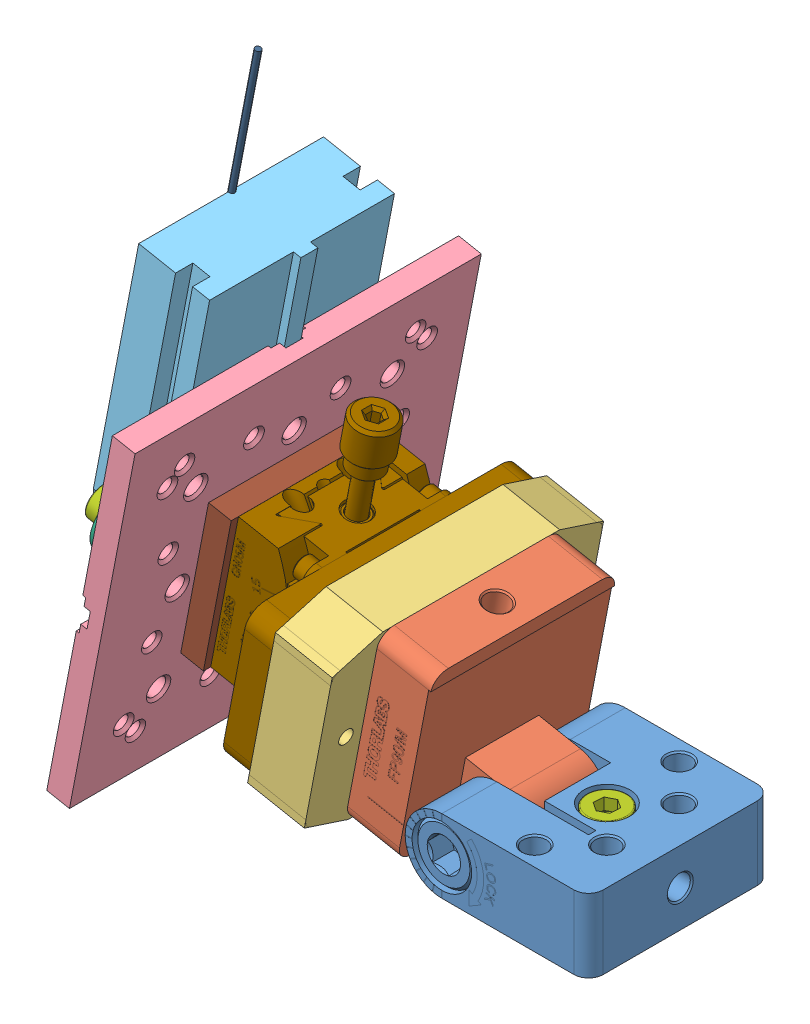
SolidWorks assembly FP90_M, configuration Default. Lengths in mm.
Overall size (94.61 108.26 59.94).
22 component instances, 12 part files, 54 mates.
Components (placement in the parent):
- FP90_M-Solidworks-1: FP90_M-Solidworks [Default] at (-4.5271 5.9477 40.2295) size (31.75 12.7 31.75)
- FP90_M-Solidworks_2-1: FP90_M-Solidworks_2 [Default] at (6.8553 4.8599 40.2422) x (0.189404 0.981899 0) z (0 0 1) size (31.75 22.1 31.75)
- Adaptador_GN05-M_FP90-M-1: Adaptador_GN05-M_FP90-M [Default] at (-11.9606 24.657 24.3481) x (0 0 -1) z (-0.981899 0.189404 0) size (47 31.7 10)
- MMP1_M-Solidworks-1: MMP1_M-Solidworks [Default] at (-31.0725 -5.8483 28.1014) x (-0.189404 -0.981899 0) z (0 0 -1) size (59.94 4.17 59.94)
- HFV002-Solidworks-1: HFV002-Solidworks [Default] at (-34.227 66.5773 14.0318) x (0 0 -1) z (0.189404 0.981899 0) size (32 13.8 82.5)
- AMA010-Solidworks-1: AMA010-Solidworks [Default] at (-49.437 40.346 4.0466) x (0.189404 0.981899 0) z (0 0 1) size (10.11 4.2 10.5)
- AMA010-Solidworks-2: AMA010-Solidworks [Default] at (-49.2897 40.3176 44.0516) x (0.189404 0.981899 0) z (0 0 1) size (10.11 4.2 10.5)
- socket head cap screw_iso_2-5: socket head cap screw_iso_2 [ISO 4762 M4 x 12 - 12N] at (-22.4725 20.3195 30.5981) x (0.981899 -0.189404 0) z (0.014939 0.077448 -0.996884) size (16 7 7)
- socket head cap screw_iso_2-6: socket head cap screw_iso_2 [ISO 4762 M3 x 8 - 8N] at (-26.521 27.4657 5.6481) x (0.981899 -0.189404 0) z (0.001715 0.008892 0.999959) size (11 5.5 5.5)
- socket head cap screw_iso_2-7: socket head cap screw_iso_2 [ISO 4762 M3 x 8 - 8N] at (-26.521 27.4657 43.0481) x (0.981899 -0.189404 0) z (0.001715 0.008892 0.999959) size (11 5.5 5.5)
- socket head cap screw_iso_2-8: socket head cap screw_iso_2 [ISO 4762 M4 x 16 - 16N] at (14.5229 18.3297 24.3545) x (0 -1 0) z (-0.546944 0 0.837169) size (20 7 7)
- plain washer small grade a_iso_2-1: plain washer small grade a_iso_2 [Washer ISO 7092 - 3] at (-49.838 39.621 4.2881) x (0.981899 -0.189404 0) z (0 0 1) size (0.5 6 6)
- plain washer small grade a_iso_2-2: plain washer small grade a_iso_2 [Washer ISO 7092 - 3] at (-49.6907 39.5926 44.2931) x (0.981899 -0.189404 0) z (0 0 1) size (0.5 6 6)
- socket head cap screw_iso_2-9: socket head cap screw_iso_2 [ISO 4762 M3 x 6 - 6N] at (-53.1274 40.2555 44.2931) x (0.981899 -0.189404 0) z (0.168238 0.872168 0.459369) size (9 5.5 5.5)
- socket head cap screw_iso_2-10: socket head cap screw_iso_2 [ISO 4762 M3 x 6 - 6N] at (-53.2747 40.284 4.2881) x (0.981899 -0.189404 0) z (-0.019637 -0.101802 0.994611) size (9 5.5 5.5)
- GN05_M-Solidworks-1: GN05_M-Solidworks [Default] at (-23.9281 14.0721 47.8381) x (0 0 -1) z (0.189404 0.981899 0) size (46.99 17.81 41.69)
- Fibra-1: Fibra [Default] at (-45.9114 101.4831 24.2961) x (-0.900159 0.173637 0.399455) z (-0.189404 -0.981899 0) size (1 1 110)
- Adapter Plate_RB10_RB18-1: Adapter Plate_RB10_RB18 [Default] at (-41.3834 17.4545 10.3021) x (0 0 1) z (-0.981899 0.189404 0) size (28 25.4 4)
- hexa csunk flathd screw_iso-1: hexa csunk flathd screw_iso [ISO 14581 M3x4x4-N] at (-46.2643 25.9416 29.5931) x (0.059216 0.306985 0.94987) z (-0.981899 0.189404 0) size (5.5 5.5 4)
- hexa csunk flathd screw_iso-2: hexa csunk flathd screw_iso [ISO 14581 M3x4x4-N] at (-46.2643 25.9416 19.0521) x (0.055614 0.288312 0.95592) z (-0.981899 0.189404 0) size (5.5 5.5 4)
- hexa csunk flathd screw_iso-3: hexa csunk flathd screw_iso [ISO 14581 M3x4x4-N] at (-44.2678 36.2918 29.5931) x (0.073929 0.383258 0.920678) z (-0.981899 0.189404 0) size (5.5 5.5 4)
- hexa csunk flathd screw_iso-4: hexa csunk flathd screw_iso [ISO 14581 M3x4x4-N] at (-44.2678 36.2918 19.0521) x (0.049785 0.25809 0.964837) z (-0.981899 0.189404 0) size (5.5 5.5 4)
Mates (geometry in assembly coordinates):
- Concentric1: concentric aligned: circle of FP90_M-Solidworks-1; circle of FP90_M-Solidworks_2-1
- Coincident1: coincident anti-aligned: plane of FP90_M-Solidworks-1 through (-4.5271 5.9477 18.0045) normal (0 0 1); plane of FP90_M-Solidworks_2-1 through (6.7306 4.8839 18.0045) normal (0 0 -1)
- Coincident27: coincident anti-aligned: plane of FP90_M-Solidworks-1 through (14.5229 14.3297 24.3545) normal (0 1 0); plane of socket head cap screw_iso-8 through (17.453 14.3297 26.2688) normal (0 -1 0)
- Concentric16: concentric aligned: cylinder of plain washer small grade a_iso-1; cylinder of socket head cap screw_iso_2-10 through (-84.45 46.2975 4.2881) axis (-0.981899 0.189404 0) radius 1.5
- Coincident31: coincident anti-aligned: plane of plain washer small grade a_iso_2-1; plane of socket head cap screw_iso_2-10
- Coincident32: coincident anti-aligned: plane of plain washer small grade a_iso_2-2; plane of socket head cap screw_iso_2-9
- Concentric21: concentric aligned: cylinder of Adaptador_GN05-M_FP90-M-1 through (-18.5449 19.5619 30.5981) axis (-0.981899 0.189404 0) radius 3.825; cylinder of socket head cap screw_iso_2-5 through (-53.6478 26.3331 30.5981) axis (-0.981899 0.189404 0) radius 2
- Coincident35: coincident anti-aligned: plane of Adaptador_GN05-M_FP90-M-1 through (-18.5449 19.5619 30.5981) normal (-0.981899 0.189404 0); plane of socket head cap screw_iso_2-5
- Coincident37: coincident anti-aligned: plane of Adaptador_GN05-M_FP90-M-1 through (-21.7796 26.5511 24.3481) normal (-0.981899 0.189404 0); plane of GN05_M-Solidworks-1
- Coincident38: coincident aligned: plane of Adaptador_GN05-M_FP90-M-1 through (-24.1851 14.081 0.8481) normal (0 0 -1); plane of GN05_M-Solidworks-1 through (14.6248 32.5037 0.8481) normal (0 0 -1)
- Concentric24: concentric anti-aligned: cylinder of Adaptador_GN05-M_FP90-M-1 through (-21.7796 26.5511 43.0481) axis (0.981899 -0.189404 0) radius 1.25; cylinder of socket head cap screw_iso_2-7 through (-57.6963 33.4793 43.0481) axis (-0.981899 0.189404 0) radius 1.5
- Coincident42: coincident anti-aligned: plane of socket head cap screw_iso_2-7; plane of GN05_M-Solidworks-1
- Concentric25: concentric anti-aligned: cylinder of Adaptador_GN05-M_FP90-M-1 through (-21.7796 26.5511 5.6481) axis (0.981899 -0.189404 0) radius 1.25; cylinder of socket head cap screw_iso_2-6 through (-57.6963 33.4793 5.6481) axis (-0.981899 0.189404 0) radius 1.5
- Coincident43: coincident anti-aligned: plane of socket head cap screw_iso_2-6; plane of GN05_M-Solidworks-1
- Concentric29: concentric anti-aligned: circle of FP90_M-Solidworks_2-1; circle of socket head cap screw_iso-5
- Parallel8: parallel aligned: plane of Adaptador_GN05-M_FP90-M-1 through (-24.1851 14.081 47.8481) normal (0 0 1); plane of GN05_M-Solidworks-1 through (14.6248 32.5037 47.8381) normal (0 0 1)
- Coincident56: coincident anti-aligned: plane of FP90_M-Solidworks_2-1; plane of Adaptador_GN05-M_FP90-M-1 through (-11.9606 24.657 24.3481) normal (0.981899 -0.189404 0)
- Coincident57: coincident anti-aligned: plane of MMP1_M-Solidworks-1 through (-44.9822 32.588 22.8211) normal (0 0 1); plane of HFV002-Solidworks-1 through (-38.3195 75.5762 22.8211) normal (0 0 -1)
- Parallel10: parallel anti-aligned: plane of MMP1_M-Solidworks-1 through (-44.9822 32.588 25.8211) normal (0 0 -1); plane of HFV002-Solidworks-1 through (-38.3195 75.5762 25.7711) normal (0 0 1)
- Coincident61: coincident anti-aligned: plane of MMP1_M-Solidworks-1; plane of HFV002-Solidworks-1
- Distance7: distance = 15 mm aligned: plane of MMP1_M-Solidworks-1 through (-41.1605 60.8477 -5.6509) normal (0.189404 0.981899 0); plane of HFV002-Solidworks-1 through (-38.3195 75.5762 25.7711) normal (0.189404 0.981899 0)
- Concentric30: concentric aligned: circle of MMP1_M-Solidworks-1; circle of AMA010-Solidworks-1
- Concentric31: concentric aligned: cylinder of AMA010-Solidworks-1 through (-49.838 39.621 4.2881) axis (-0.981899 0.189404 0) radius 1.9; cylinder of socket head cap screw_iso_2-10 through (-84.45 46.2975 4.2881) axis (-0.981899 0.189404 0) radius 1.5
- Coincident66: coincident anti-aligned: plane of AMA010-Solidworks-1; plane of HFV002-Solidworks-1
- Coincident67: coincident anti-aligned: plane of AMA010-Solidworks-1; plane of plain washer small grade a_iso_2-1
- Coincident68: coincident anti-aligned: cone of MMP1_M-Solidworks-1 through (-45.4195 38.7687 44.2931) axis (0.981899 -0.189404 0); circle of AMA010-Solidworks-2
- Coincident69: coincident anti-aligned: plane of AMA010-Solidworks-2; plane of plain washer small grade a_iso_2-2
- Concentric32: concentric aligned: circle of AMA010-Solidworks-2; circle of plain washer small grade a_iso-2
- Concentric33: concentric aligned: circle of plain washer small grade a_iso-2; cylinder of socket head cap screw_iso_2-9 through (-84.3027 46.2691 44.2931) axis (-0.981899 0.189404 0) radius 1.5
- Distance10: distance = 3.11 mm aligned: plane of Adaptador_GN05-M_FP90-M-1 through (-8.9586 40.2201 39.6581) normal (0.189404 0.981899 0); plane of GN05_M-Solidworks-1 through (14.6248 32.5037 24.3431) normal (0.189404 0.981899 0)
- Concentric34: concentric aligned: cylinder of HFV002-Solidworks-1 through (-66.0829 -3.0892 24.2961) axis (0.189404 0.981899 0) radius 0.03; cylinder of Fibra-1 through (-62.9578 13.1121 24.2961) axis (0.189404 0.981899 0) radius 0.5
- Distance11: distance = 24 mm aligned: plane of Fibra-1 through (-45.9114 101.4831 24.2961) normal (0.189404 0.981899 0); plane of HFV002-Solidworks-1 through (-38.3195 75.5762 25.7711) normal (0.189404 0.981899 0)
- Coincident70: coincident anti-aligned: plane of GN05_M-Solidworks-1; plane of Adapter Plate_RB10_RB18-1
- Parallel11: parallel aligned: cylinder of GN05_M-Solidworks-1 through (-40.6646 21.1808 17.9931) axis (-0.981899 0.189404 0) radius 1.25; cylinder of Adapter Plate_RB10_RB18-1 through (-41.0395 24.5172 13.8021) axis (-0.981899 0.189404 0) radius 3
- Concentric37: concentric aligned: circle of GN05_M-Solidworks-1; circle of Adapter Plate_RB10_RB18-1
- Parallel12: parallel aligned: plane of GN05_M-Solidworks-1; plane of Adapter Plate_RB10_RB18-1
- Parallel13: parallel aligned: plane of GN05_M-Solidworks-1 through (-22.6811 13.8316 37.0431) normal (0 0 1); plane of Adapter Plate_RB10_RB18-1 through (-45.311 18.2121 38.3021) normal (0 0 1)
- Coincident73: coincident anti-aligned: plane of MMP1_M-Solidworks-1; plane of Adapter Plate_RB10_RB18-1
- Concentric42: concentric aligned: circle of MMP1_M-Solidworks-1; circle of Adapter Plate_RB10_RB18-1
- Parallel14: parallel aligned: plane of MMP1_M-Solidworks-1; plane of Adapter Plate_RB10_RB18-1
- Parallel15: parallel aligned: plane of MMP1_M-Solidworks-1 through (-41.1605 60.8477 54.2931) normal (0 0 1); plane of Adapter Plate_RB10_RB18-1 through (-45.311 18.2121 38.3021) normal (0 0 1)
- Concentric43: concentric anti-aligned: cylinder of MMP1_M-Solidworks-1 through (-45.8388 36.5948 19.0521) axis (-0.981899 0.189404 0) radius 1.6; cylinder of hexa csunk flathd screw_iso-4 through (-44.2678 36.2918 19.0521) axis (0.981899 -0.189404 0) radius 1.5
- Concentric44: concentric anti-aligned: cylinder of MMP1_M-Solidworks-1 through (-45.8388 36.5948 29.5931) axis (-0.981899 0.189404 0) radius 1.6; cylinder of hexa csunk flathd screw_iso-3 through (-44.2678 36.2918 29.5931) axis (0.981899 -0.189404 0) radius 1.5
- Concentric45: concentric anti-aligned: cylinder of MMP1_M-Solidworks-1 through (-47.8353 26.2446 19.0521) axis (-0.981899 0.189404 0) radius 1.6; cylinder of hexa csunk flathd screw_iso-2 through (-46.2643 25.9416 19.0521) axis (0.981899 -0.189404 0) radius 1.5
- Concentric46: concentric anti-aligned: cylinder of MMP1_M-Solidworks-1 through (-47.8353 26.2446 29.5931) axis (-0.981899 0.189404 0) radius 1.6; cylinder of hexa csunk flathd screw_iso-1 through (-46.2643 25.9416 29.5931) axis (0.981899 -0.189404 0) radius 1.5
- Coincident76: coincident anti-aligned: plane of MMP1_M-Solidworks-1; circle of hexa csunk flathd screw_iso-1
- Coincident77: coincident anti-aligned: plane of MMP1_M-Solidworks-1; circle of hexa csunk flathd screw_iso-2
- Coincident78: coincident anti-aligned: plane of MMP1_M-Solidworks-1; circle of hexa csunk flathd screw_iso-3
- Coincident79: coincident anti-aligned: plane of MMP1_M-Solidworks-1; circle of hexa csunk flathd screw_iso-4
- Parallel16: parallel aligned: plane of FP90_M-Solidworks_2-1; plane of Adaptador_GN05-M_FP90-M-1 through (-8.9586 40.2201 39.6581) normal (0.189404 0.981899 0)
- Parallel18: parallel aligned: plane of MMP1_M-Solidworks-1 through (-41.1605 60.8477 -5.6509) normal (0.189404 0.981899 0); plane of Adapter Plate_RB10_RB18-1 through (-40.5001 43.1523 10.3021) normal (0.189404 0.981899 0)
- Parallel19: parallel aligned: plane of GN05_M-Solidworks-1 through (-17.8702 38.7718 24.3431) normal (0.189404 0.981899 0); plane of Adapter Plate_RB10_RB18-1 through (-40.5001 43.1523 10.3021) normal (0.189404 0.981899 0)
- Parallel20: parallel aligned: plane of GN05_M-Solidworks-1 through (14.6248 32.5037 24.3431) normal (0.189404 0.981899 0); plane of Adapter Plate_RB10_RB18-1 through (-40.5001 43.1523 10.3021) normal (0.189404 0.981899 0)
- Parallel21: parallel aligned: plane of Adaptador_GN05-M_FP90-M-1 through (-8.9586 40.2201 39.6581) normal (0.189404 0.981899 0); plane of GN05_M-Solidworks-1 through (14.6248 32.5037 24.3431) normal (0.189404 0.981899 0)
